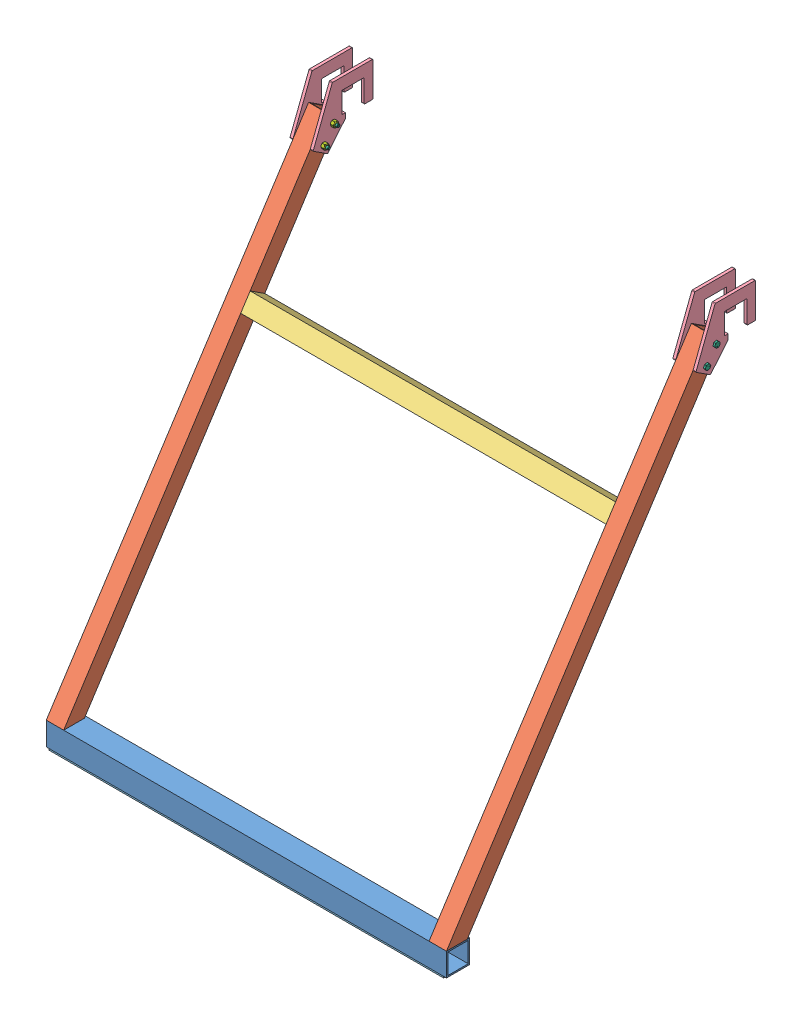
SolidWorks assembly GE-19120, configuration Default. Lengths in mm.
Overall size (896.94 994.41 670.84).
18 component instances, 7 part files, 27 mates.
Components (placement in the parent):
- GE-19118-1: GE-19118 [Default] at origin size (876.3 935.22 606.3)
  - GE-19118-01-1: GE-19118-01 [Default] at origin size (876.3 50.8 50.8)
  - GE-19118-03-1: GE-19118-03 [Default] at (-438.15 0 -407.3116) size (38.1 884.42 606.3)
  - GE-19118-03-2: GE-19118-03 [Default] at (400.05 0 -407.3116) size (38.1 884.42 606.3)
  - GE-19118-02-1: GE-19118-02 [Default] at (-400.05 647.643 -387.5944) x (1 0 0) z (0 0.544639 0.838671) size (800.1 38.1 38.1)
- GE-19119-1: GE-19119 [Default] at (-444.5 0 -407.3116) size (6.35 129.5 130.71)
- GE-19119-2: GE-19119 [Default] at (-400.05 0 -407.3116) size (6.35 129.5 130.71)
- GE-19119-3: GE-19119 [Default] at (393.7 0 -407.3116) size (6.35 129.5 130.71)
- GE-19119-4: GE-19119 [Default] at (438.15 0 -407.3116) size (6.35 129.5 130.71)
- Hook_2_34-1: Hook_2_34 [Default] at (431.8 0 0) x (1 0 0) z (0 -1 0) size (863.6 50.8 3.17)
- hex_.25_20_2.5_partial-1: hex_.25_20_2.5_partial [91247A552] at (-414.7344 882.2433 -562.6601) size (67.47 12.83 11.11)
- hex_.25_20_2.5_partial-2: hex_.25_20_2.5_partial [91247A552] at (-414.7344 914.1967 -583.4109) x (1 0 0) z (0 -0.158553 0.987351) size (67.47 12.83 11.11)
- hex_.25_20_2.5_partial-4: hex_.25_20_2.5_partial [91247A552] at (414.7344 914.1967 -583.4109) x (-1 0 0) z (0 0.282984 0.959125) size (67.47 12.83 11.11)
- hex_.25_20_2.5_partial-6: hex_.25_20_2.5_partial [91247A552] at (414.7344 882.2433 -562.6601) x (-1 0 0) z (0 0.371154 0.928571) size (67.47 12.83 11.11)
- nylock_.25_20-1: nylock_.25_20 [Default] at (-393.7 914.1967 -583.4109) x (0 0.381849 -0.924225) z (0 -0.924225 -0.381849) size (11.11 7.94 12.83)
- nylock_.25_20-2: nylock_.25_20 [Default] at (-393.7 882.2433 -562.6601) x (0 0.523557 -0.85199) z (0 -0.85199 -0.523557) size (11.11 7.94 12.83)
- nylock_.25_20-4: nylock_.25_20 [Default] at (393.7 914.1967 -583.4109) x (0 0.737887 -0.674924) z (0 0.674924 0.737887) size (11.11 7.94 12.83)
- nylock_.25_20-6: nylock_.25_20 [Default] at (393.7 882.2433 -562.6601) x (0 0.609477 -0.792804) z (0 0.792804 0.609477) size (11.11 7.94 12.83)
Mates (geometry in assembly coordinates):
- Coincident1: coincident: circle of GE-19118-1/GE-19118-03-1; circle of GE-19119-2
- Coincident2: coincident: circle of GE-19118-1/GE-19118-03-1; circle of GE-19119-2
- Coincident3: coincident: circle of GE-19118-1/GE-19118-03-1; circle of GE-19119-1
- Coincident4: coincident: circle of GE-19118-1/GE-19118-03-1; circle of GE-19119-1
- Coincident5: coincident: circle of GE-19118-1/GE-19118-03-2; circle of GE-19119-4
- Coincident6: coincident: circle of GE-19118-1/GE-19118-03-2; circle of GE-19119-4
- Coincident7: coincident: circle of GE-19118-1/GE-19118-03-2; circle of GE-19119-3
- Coincident8: coincident: circle of GE-19118-1/GE-19118-03-2; circle of GE-19119-3
- Coincident23: coincident: plane of GE-19118-1/GE-19118-01-1 through (-438.15 0 0) normal (0 -1 0); plane of Hook_2_34-1 through (431.8 0 0) normal (0 1 0)
- Coincident24: coincident: plane of GE-19118-1/GE-19118-01-1 through (-438.15 0 -50.8) normal (0 0 -1); plane of Hook_2_34-1 through (431.8 -3.175 -50.8) normal (0 0 -1)
- Width1: width: plane of Hook_2_34-1 through (431.8 -3.175 0) normal (1 0 0); plane of Hook_2_34-1 through (-431.8 -3.175 0) normal (-1 0 0); plane of GE-19118-1/GE-19118-01-1 through (438.15 0 0) normal (1 0 0); plane of GE-19118-1/GE-19118-01-1 through (-438.15 0 0) normal (-1 0 0)
- Concentric1: concentric: cylinder of assembly; cylinder of assembly; cylinder of GE-19119-1 through (-444.5 882.2433 -562.6601) axis (-1 0 0) radius 3.3782; cylinder of hex_.25_20_2.5_partial-1 through (-444.5 882.2433 -562.6601) axis (1 0 0) radius 3.175
- Coincident25: coincident: plane of assembly; plane of assembly; plane of GE-19119-1 through (-444.5 0 -407.3116) normal (-1 0 0); plane of hex_.25_20_2.5_partial-1 through (-444.5 885.4512 -557.1039) normal (1 0 0)
- Concentric2: concentric: cylinder of assembly; cylinder of assembly; cylinder of GE-19119-1 through (-444.5 914.1967 -583.4109) axis (-1 0 0) radius 3.3782; cylinder of hex_.25_20_2.5_partial-2 through (-444.5 914.1967 -583.4109) axis (1 0 0) radius 3.175
- Coincident26: coincident: plane of assembly; plane of assembly; plane of GE-19119-1 through (-444.5 0 -407.3116) normal (-1 0 0); plane of hex_.25_20_2.5_partial-2 through (-444.5 916.483 -577.4163) normal (1 0 0)
- Concentric3: concentric: cylinder of assembly; cylinder of assembly; cylinder of GE-19119-4 through (438.15 914.1967 -583.4109) axis (-1 0 0) radius 3.3782; cylinder of hex_.25_20_2.5_partial-4 through (444.5 914.1967 -583.4109) axis (-1 0 0) radius 3.175
- Coincident27: coincident: plane of assembly; plane of assembly; plane of GE-19119-4 through (444.5 0 -407.3116) normal (1 0 0); plane of hex_.25_20_2.5_partial-4 through (444.5 912.6922 -577.1739) normal (-1 0 0)
- Concentric4: concentric: cylinder of assembly; cylinder of assembly; cylinder of GE-19119-4 through (438.15 882.2433 -562.6601) axis (-1 0 0) radius 3.3782; cylinder of hex_.25_20_2.5_partial-6 through (444.5 882.2433 -562.6601) axis (-1 0 0) radius 3.175
- Coincident28: coincident: plane of assembly; plane of assembly; plane of GE-19119-4 through (444.5 0 -407.3116) normal (1 0 0); plane of hex_.25_20_2.5_partial-6 through (444.5 881.3268 -556.3101) normal (-1 0 0)
- Concentric5: concentric: cylinder of assembly; cylinder of assembly; cylinder of hex_.25_20_2.5_partial-2 through (-444.5 914.1967 -583.4109) axis (1 0 0) radius 3.175; cylinder of nylock_.25_20-1 through (-393.7 914.1967 -583.4109) axis (1 0 0) radius 3.175
- Coincident29: coincident: plane of assembly; plane of assembly; plane of GE-19119-2 through (-393.7 0 -407.3116) normal (1 0 0); plane of nylock_.25_20-1 through (-393.7 914.1967 -583.4109) normal (-1 0 0)
- Concentric6: concentric: cylinder of assembly; cylinder of assembly; cylinder of hex_.25_20_2.5_partial-1 through (-444.5 882.2433 -562.6601) axis (1 0 0) radius 3.175; cylinder of nylock_.25_20-2 through (-393.7 882.2433 -562.6601) axis (1 0 0) radius 3.175
- Coincident30: coincident: plane of assembly; plane of assembly; plane of GE-19119-2 through (-393.7 0 -407.3116) normal (1 0 0); plane of nylock_.25_20-2 through (-393.7 882.2433 -562.6601) normal (-1 0 0)
- Concentric7: concentric: cylinder of assembly; cylinder of assembly; cylinder of hex_.25_20_2.5_partial-4 through (444.5 914.1967 -583.4109) axis (-1 0 0) radius 3.175; cylinder of nylock_.25_20-4 through (393.7 914.1967 -583.4109) axis (-1 0 0) radius 3.175
- Coincident31: coincident: plane of assembly; plane of assembly; plane of GE-19119-3 through (393.7 0 -407.3116) normal (-1 0 0); plane of nylock_.25_20-4 through (393.7 914.1967 -583.4109) normal (1 0 0)
- Concentric8: concentric: cylinder of assembly; cylinder of assembly; cylinder of hex_.25_20_2.5_partial-6 through (444.5 882.2433 -562.6601) axis (-1 0 0) radius 3.175; cylinder of nylock_.25_20-6 through (393.7 882.2433 -562.6601) axis (-1 0 0) radius 3.175
- Coincident32: coincident: plane of assembly; plane of assembly; plane of GE-19119-3 through (393.7 0 -407.3116) normal (-1 0 0); plane of nylock_.25_20-6 through (393.7 882.2433 -562.6601) normal (1 0 0)
